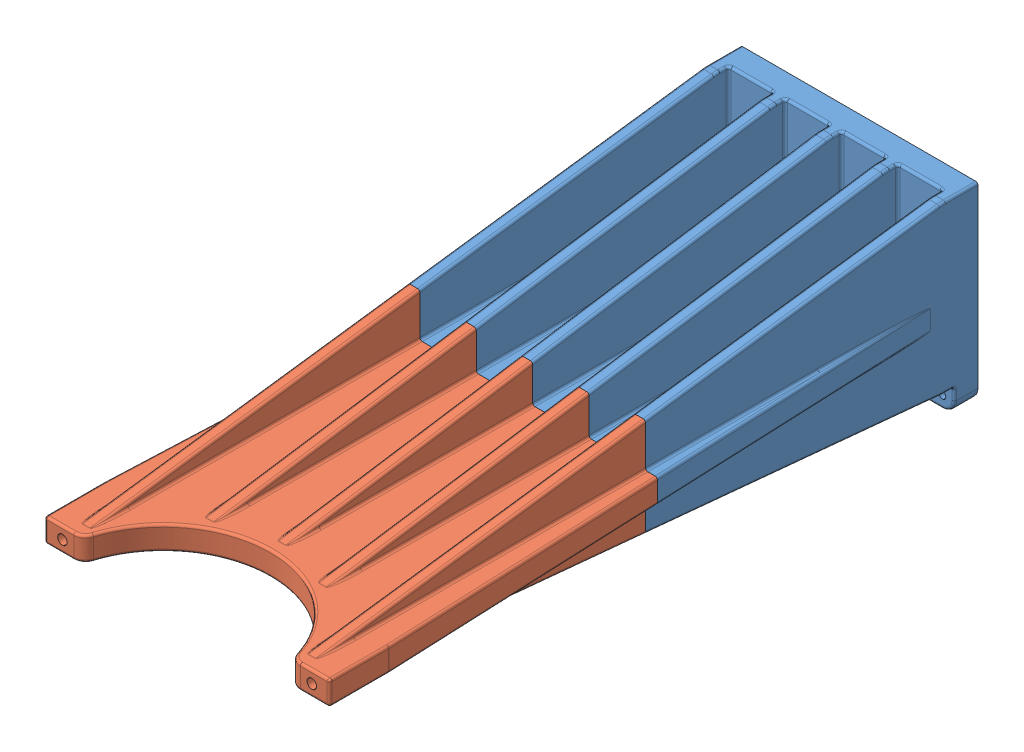
SolidWorks assembly calibration_platform_2022-08-09, configuration Default. Lengths in mm.
Overall size (120 80 283).
2 component instances, 2 part files, 6 mates.
Components (placement in the parent):
- calibration_platform-1: calibration_platform [Default] at origin size (110.08 80 140)
- calibration_platform_upper-1: calibration_platform_upper [Default] at origin size (120 44.73 143)
Mates (geometry in assembly coordinates):
- Coincident1: coincident aligned: plane of calibration_platform-1 through (0 0 0) normal (0 0 1)
- Coincident2: coincident aligned: plane of calibration_platform-1 through (0 0 0) normal (0 1 0)
- Coincident3: coincident aligned: plane of calibration_platform-1 through (0 0 0) normal (1 0 0)
- Concentric1: concentric anti-aligned: cylinder of calibration_platform-1 through (-47.5 0 130) axis (0 0 1) radius 1.45; cylinder of calibration_platform_upper-1 through (-47.5 0 160) axis (0 0 -1) radius 1.45
- Concentric2: concentric anti-aligned: cylinder of calibration_platform-1 through (47.5 0 130) axis (0 0 1) radius 1.45; cylinder of calibration_platform_upper-1 through (47.5 0 160) axis (0 0 -1) radius 1.45
- Coincident4: coincident anti-aligned: plane of calibration_platform-1 through (0 0 140) normal (0 0 1); plane of calibration_platform_upper-1 through (0 0 140) normal (0 0 -1)
